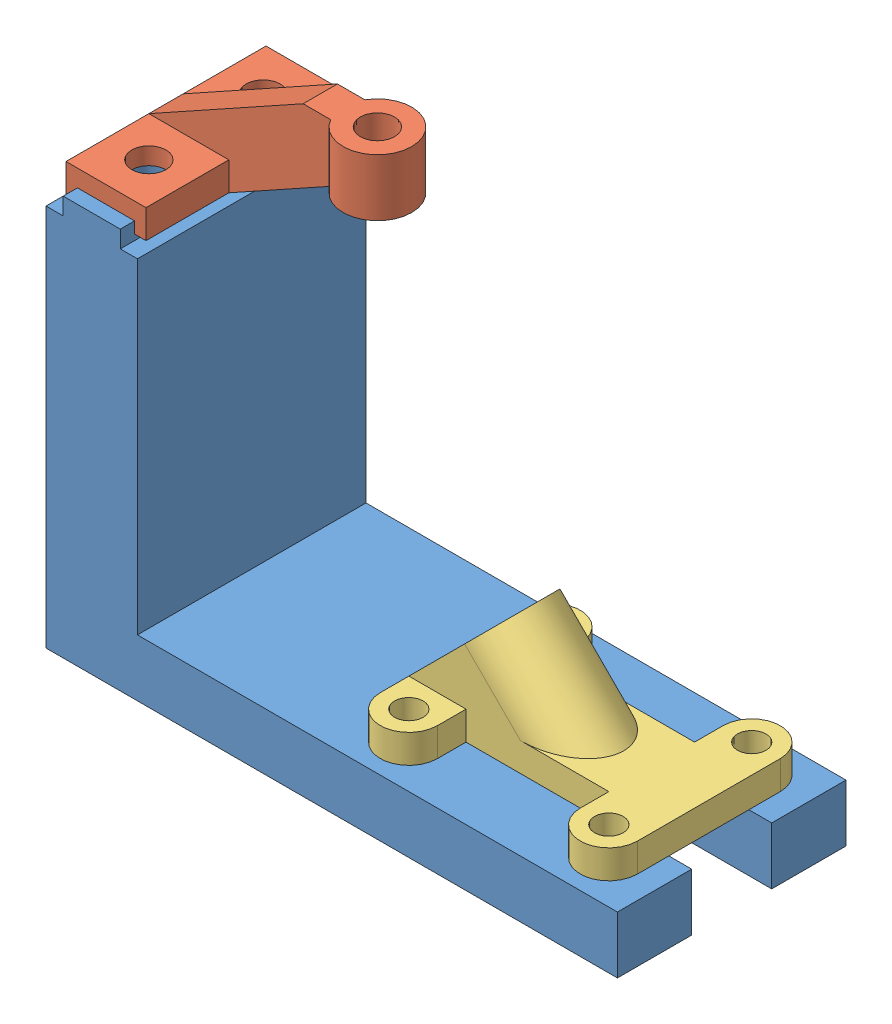
SolidWorks assembly 110303047-91, configuration 預設. Lengths in mm.
Overall size (100 88 40).
3 component instances, 3 part files, 6 mates.
Components (placement in the parent):
- Part-1-1: Part-1 [預設] at (-53.1295 -38.1073 100) size (100 70 40)
- Part-2-1: Part-2 [預設] at (-61.1295 24.8927 100) size (43 20 35)
- Part-3-1: Part-3 [預設] at (4.3705 -38.1073 100) size (45 20.06 35)
Mates (geometry in assembly coordinates):
- 同軸心1: concentric: circle of 110303047-91-1; circle of 110303047-92-1
- 同軸心2: concentric: circle of 110303047-91-1; circle of 110303047-92-1
- 重合/共線/共點3: coincident anti-aligned: plane of 110303047-91-1 through (-66.1295 21.8927 120) normal (0 1 0); plane of 110303047-92-1 through (-56.1295 21.8927 117.5) normal (0 -1 0)
- 同軸心3: concentric: cylinder of 110303047-91-1 through (-13.1295 -48.1073 112.5) axis (0 1 0) radius 2.5; cylinder of 110303047-93-1 through (-13.1295 -33.1073 112.5) axis (0 -1 0) radius 2.5
- 同軸心4: concentric: cylinder of 110303047-91-1 through (-13.1295 -48.1073 87.5) axis (0 1 0) radius 2.5; cylinder of 110303047-93-1 through (-13.1295 -33.1073 87.5) axis (0 -1 0) radius 2.5
- 重合/共線/共點4: coincident anti-aligned: plane of 110303047-91-1 through (-53.1295 -38.1073 120) normal (0 1 0); plane of 110303047-93-1 through (-13.1295 -38.1073 87.5) normal (0 -1 0)
